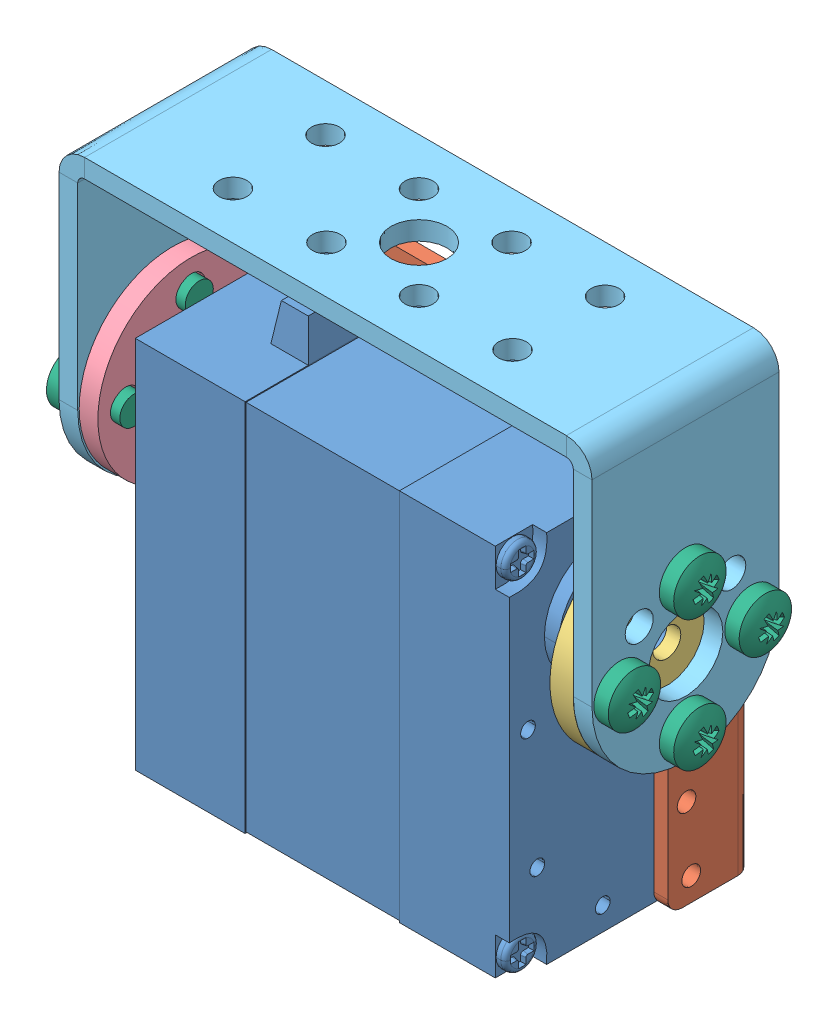
SolidWorks assembly 装配体9, configuration 默认. Lengths in mm.
Overall size (61.71 54.2 24.77).
14 component instances, 6 part files, 28 mates.
Components (placement in the parent):
- 双轴舵机-1: 双轴舵机 [默认] at (2.8169 12.8625 41) size (51 44 20)
- 侧面支架-1: 侧面支架 [默认] at (3.0669 12.8625 37.0428) x (1 0 0) z (0 -1 0) size (43.5 9 40)
- 金属主舵盘-1: 金属主舵盘 [默认] at (29.8169 23.2637 51.1556) x (0 1 0) z (0 0 1) size (20 4.5 20)
- 金属从舵盘-1: 金属从舵盘 [默认] at (-23.1831 23.3625 51) x (0 0 -1) z (1 0 0) size (20 20 3)
- 宽U支架-1: 宽U支架 [默认] at (-11.1036 36.2094 61.1556) x (1 0 0) z (0 0 -1) size (57 33.8 20)
- GB_CROSS_SCREWS_TYPE1 M3X5-5  Z type-N-1: GB_CROSS_SCREWS_TYPE1 M3X5-5  Z type-N [GB_CROSS_SCREWS_TYPE1 M3X5-5  Z type-N] at (-27.5831 30.2637 51.1556) size (7.35 5.6 5.6)
- GB_CROSS_SCREWS_TYPE1 M3X5-5  Z type-N-2: GB_CROSS_SCREWS_TYPE1 M3X5-5  Z type-N [GB_CROSS_SCREWS_TYPE1 M3X5-5  Z type-N] at (-27.5831 16.2637 51.1556) size (7.35 5.6 5.6)
- GB_CROSS_SCREWS_TYPE1 M3X5-5  Z type-N-3: GB_CROSS_SCREWS_TYPE1 M3X5-5  Z type-N [GB_CROSS_SCREWS_TYPE1 M3X5-5  Z type-N] at (-27.5831 23.2637 58.1556) size (7.35 5.6 5.6)
- GB_CROSS_SCREWS_TYPE1 M3X5-5  Z type-N-4: GB_CROSS_SCREWS_TYPE1 M3X5-5  Z type-N [GB_CROSS_SCREWS_TYPE1 M3X5-5  Z type-N] at (-27.5831 23.2637 44.1556) size (7.35 5.6 5.6)
- GB_CROSS_SCREWS_TYPE1 M3X5-5  Z type-N-5: GB_CROSS_SCREWS_TYPE1 M3X5-5  Z type-N [GB_CROSS_SCREWS_TYPE1 M3X5-5  Z type-N] at (-25.5831 23.3625 51) size (7.35 5.6 5.6)
- GB_CROSS_SCREWS_TYPE1 M3X5-5  Z type-N-6: GB_CROSS_SCREWS_TYPE1 M3X5-5  Z type-N [GB_CROSS_SCREWS_TYPE1 M3X5-5  Z type-N] at (34.2169 23.2637 44.1556) x (-1 0 0) z (0 -0.924225 -0.381849) size (7.35 5.6 5.6)
- GB_CROSS_SCREWS_TYPE1 M3X5-5  Z type-N-7: GB_CROSS_SCREWS_TYPE1 M3X5-5  Z type-N [GB_CROSS_SCREWS_TYPE1 M3X5-5  Z type-N] at (34.2169 30.2637 51.1556) x (-1 0 0) z (0 -0.924225 -0.381849) size (7.35 5.6 5.6)
- GB_CROSS_SCREWS_TYPE1 M3X5-5  Z type-N-8: GB_CROSS_SCREWS_TYPE1 M3X5-5  Z type-N [GB_CROSS_SCREWS_TYPE1 M3X5-5  Z type-N] at (34.2169 23.2637 58.1556) x (-1 0 0) z (0 -0.924225 -0.381849) size (7.35 5.6 5.6)
- GB_CROSS_SCREWS_TYPE1 M3X5-5  Z type-N-9: GB_CROSS_SCREWS_TYPE1 M3X5-5  Z type-N [GB_CROSS_SCREWS_TYPE1 M3X5-5  Z type-N] at (34.2169 16.2637 51.1556) x (-1 0 0) z (0 -0.924225 -0.381849) size (7.35 5.6 5.6)
Mates (geometry in assembly coordinates):
- 同心2: concentric anti-aligned: cylinder of 双轴舵机-1 through (-12.1831 30.3625 43.5428) axis (-1 0 0) radius 0.79; cylinder of 侧面支架-1 through (-17.9331 30.3625 43.5428) axis (1 0 0) radius 1
- 重合1: coincident anti-aligned: plane of 双轴舵机-1 through (-17.1831 -7.1375 61) normal (-1 0 0); plane of 侧面支架-1 through (-17.1831 -7.1375 37.0428) normal (1 0 0)
- 同心3: concentric anti-aligned: cylinder of 双轴舵机-1 through (-12.1831 10.3625 43.5428) axis (-1 0 0) radius 0.79; circle of 侧面支架-1
- 重合2: coincident anti-aligned: plane of 双轴舵机-1 through (28.3169 24.3942 50.1505) normal (1 0 0); plane of 金属主舵盘-1 through (28.3169 23.2637 51.1556) normal (-1 0 0)
- 同心4: concentric anti-aligned: cylinder of 双轴舵机-1 through (24.3169 23.2637 51.1556) axis (1 0 0) radius 1.5; cylinder of 金属主舵盘-1 through (29.8169 23.2637 51.1556) axis (-1 0 0) radius 1.5
- 同心5: concentric anti-aligned: cylinder of 双轴舵机-1 through (-18.6831 23.3625 51) axis (-1 0 0) radius 1.5; cylinder of 金属从舵盘-1 through (-23.1831 23.3625 51) axis (1 0 0) radius 3
- 重合3: coincident anti-aligned: plane of 金属主舵盘-1 through (29.8169 23.2637 51.1556) normal (1 0 0); plane of 宽U支架-1 through (29.8169 45.0637 41.1556) normal (-1 0 0)
- 同心6: concentric aligned: cylinder of 金属主舵盘-1 through (29.8169 23.2637 51.1556) axis (-1 0 0) radius 1.5; cylinder of 宽U支架-1 through (31.8169 23.2637 51.1556) axis (-1 0 0) radius 4
- 重合5: coincident anti-aligned: plane of 金属从舵盘-1 through (-23.1831 23.3625 51) normal (-1 0 0); plane of 宽U支架-1 through (-23.1831 23.2637 41.1556) normal (1 0 0)
- 平行1: parallel aligned: line of 侧面支架-1 through (-18.6831 -7.1375 38.5428) axis (0 1 0); line of 宽U支架-1 through (-25.1831 23.2637 41.1556) axis (0 1 0)
- 重合7: coincident: plane of 宽U支架-1 through (-25.1831 23.2637 41.1556) normal (-1 0 0); plane of GB_CROSS_SCREWS_TYPE1 M3X5-5  Z type-N-1 through (-25.1831 32.0637 51.1556) normal (1 0 0)
- 同心7: concentric anti-aligned: cylinder of 宽U支架-1 through (31.8169 30.2637 51.1556) axis (-1 0 0) radius 1.5; cylinder of GB_CROSS_SCREWS_TYPE1 M3X5-5  Z type-N-1 through (-23.0672 30.2637 51.1556) axis (1 0 0) radius 1.5
- 重合8: coincident: plane of 宽U支架-1 through (-25.1831 23.2637 41.1556) normal (-1 0 0); plane of GB_CROSS_SCREWS_TYPE1 M3X5-5  Z type-N-2 through (-25.1831 18.0637 51.1556) normal (1 0 0)
- 同心8: concentric anti-aligned: cylinder of 宽U支架-1 through (31.8169 16.2637 51.1556) axis (-1 0 0) radius 1.5; cylinder of GB_CROSS_SCREWS_TYPE1 M3X5-5  Z type-N-2 through (-23.0672 16.2637 51.1556) axis (1 0 0) radius 1.5
- 重合9: coincident: plane of 宽U支架-1 through (-25.1831 23.2637 41.1556) normal (-1 0 0); plane of GB_CROSS_SCREWS_TYPE1 M3X5-5  Z type-N-3 through (-25.1831 25.0637 58.1556) normal (1 0 0)
- 重合10: coincident anti-aligned: circle of 宽U支架-1; cylinder of GB_CROSS_SCREWS_TYPE1 M3X5-5  Z type-N-3 through (-23.0672 23.2637 58.1556) axis (1 0 0) radius 1.5
- 重合11: coincident: plane of 宽U支架-1 through (-25.1831 23.2637 41.1556) normal (-1 0 0); plane of GB_CROSS_SCREWS_TYPE1 M3X5-5  Z type-N-4 through (-25.1831 25.0637 44.1556) normal (1 0 0)
- 同心9: concentric anti-aligned: cylinder of 宽U支架-1 through (31.8169 23.2637 44.1556) axis (-1 0 0) radius 1.5; cylinder of GB_CROSS_SCREWS_TYPE1 M3X5-5  Z type-N-4 through (-23.0672 23.2637 44.1556) axis (1 0 0) radius 1.5
- 重合12: coincident anti-aligned: plane of 金属从舵盘-1 through (-23.1831 23.3625 51) normal (-1 0 0); plane of GB_CROSS_SCREWS_TYPE1 M3X5-5  Z type-N-5 through (-23.1831 25.1625 51) normal (1 0 0)
- 同心10: concentric anti-aligned: cylinder of 双轴舵机-1 through (-18.6831 23.3625 51) axis (-1 0 0) radius 1.5; cylinder of GB_CROSS_SCREWS_TYPE1 M3X5-5  Z type-N-5 through (-21.0672 23.3625 51) axis (1 0 0) radius 1.5
- 重合13: coincident: plane of 宽U支架-1 through (31.8169 45.0637 41.1556) normal (1 0 0); plane of GB_CROSS_SCREWS_TYPE1 M3X5-5  Z type-N-6 through (31.8169 23.951 42.492) normal (-1 0 0)
- 同心11: concentric aligned: cylinder of 宽U支架-1 through (31.8169 23.2637 44.1556) axis (-1 0 0) radius 1.5; cylinder of GB_CROSS_SCREWS_TYPE1 M3X5-5  Z type-N-6 through (29.7011 23.2637 44.1556) axis (-1 0 0) radius 1.5
- 重合14: coincident: plane of 宽U支架-1 through (31.8169 45.0637 41.1556) normal (1 0 0); plane of GB_CROSS_SCREWS_TYPE1 M3X5-5  Z type-N-7 through (31.8169 30.951 49.492) normal (-1 0 0)
- 同心12: concentric aligned: cylinder of 宽U支架-1 through (31.8169 30.2637 51.1556) axis (-1 0 0) radius 1.5; cylinder of GB_CROSS_SCREWS_TYPE1 M3X5-5  Z type-N-7 through (29.7011 30.2637 51.1556) axis (-1 0 0) radius 1.5
- 重合15: coincident: plane of 宽U支架-1 through (31.8169 45.0637 41.1556) normal (1 0 0); plane of GB_CROSS_SCREWS_TYPE1 M3X5-5  Z type-N-8 through (31.8169 23.951 56.492) normal (-1 0 0)
- 同心13: concentric aligned: cylinder of 宽U支架-1 through (31.8169 23.2637 58.1556) axis (-1 0 0) radius 1.5; cylinder of GB_CROSS_SCREWS_TYPE1 M3X5-5  Z type-N-8 through (29.7011 23.2637 58.1556) axis (-1 0 0) radius 1.5
- 重合16: coincident: plane of 宽U支架-1 through (31.8169 45.0637 41.1556) normal (1 0 0); plane of GB_CROSS_SCREWS_TYPE1 M3X5-5  Z type-N-9 through (31.8169 16.951 49.492) normal (-1 0 0)
- 同心14: concentric aligned: cylinder of 宽U支架-1 through (31.8169 16.2637 51.1556) axis (-1 0 0) radius 1.5; circle of GB_CROSS_SCREWS_TYPE1 M3X5-5  Z type-N-9
